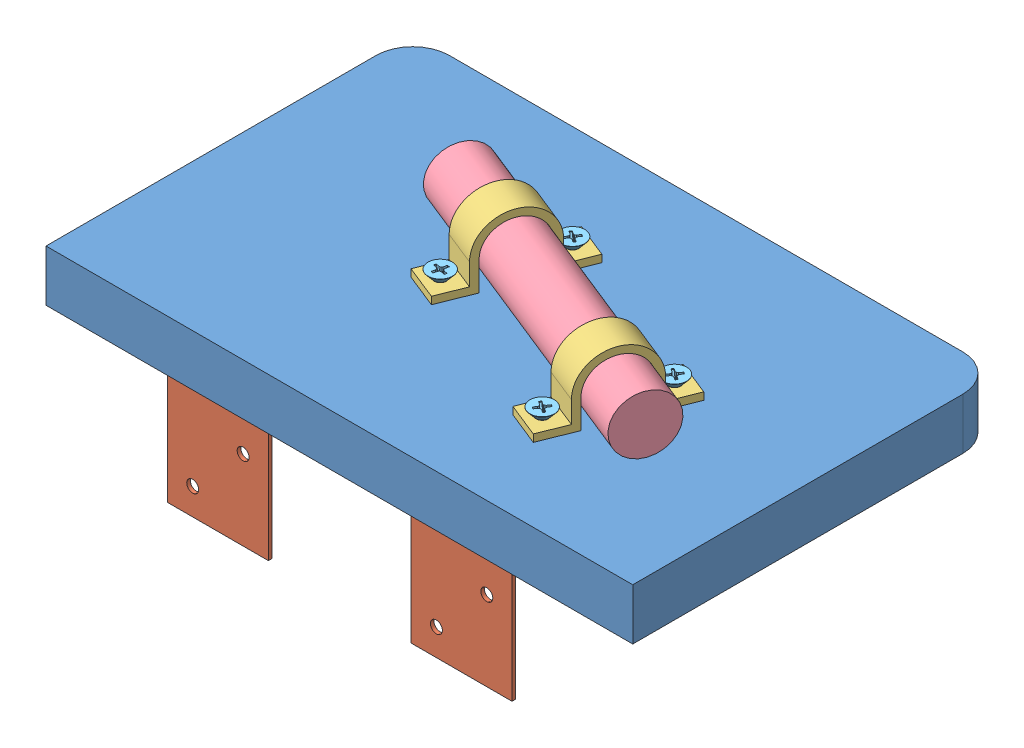
SolidWorks assembly Assemsight, configuration Default. Lengths in mm.
Overall size (203.2 82.02 127).
16 component instances, 7 part files, 18 mates.
Components (placement in the parent):
- RampSight-1: RampSight [Default] at (38.0656 138.4152 220.9267) size (203.2 17.78 127)
- screwangle-1: screwangle [Default] at (-4.0031 138.4152 259.014) x (0 0 -1) z (0 -1 0) size (50.8 34.92 38.1)
- screwangle-2: screwangle [Default] at (80.3757 138.4152 259.014) x (0 0 -1) z (0 -1 0) size (50.8 34.92 38.1)
- LaserStrap-3: LaserStrap [Default] at (76.1001 166.1978 233.9353) x (0.37234 0 -0.928096) z (0.928096 0 0.37234) size (45.4 22.54 12.7)
- LaserStrap-4: LaserStrap [Default] at (17.166 166.1978 210.2918) x (0.37234 0 -0.928096) z (0.928096 0 0.37234) size (45.4 22.54 12.7)
- laserpointereal-3: laserpointereal [Default] at (-2.9774 166.1952 201.3092) x (-0.371391 0.071332 0.925732) z (0.928096 0 0.37234) size (30.2 30.2 115)
- Part1^Assemsight-1: Part1^Assemsight [Default] at origin (virtual)
- Part2^Assemsight-1: Part2^Assemsight [Default] at origin (virtual)
- sightscrew-1: sightscrew [90031A194] at (16.8102 154.9836 228.2328) x (0 -1 0) z (-0.202266 0 0.979331) size (12.7 8.43 8.43)
- sightscrew-2: sightscrew [90031A194] at (-12.7344 140.9552 245.9965) x (0 1 0) z (-0.546944 0 0.837169) size (12.7 8.43 8.43)
- sightscrew-3: sightscrew [90031A194] at (88.8656 154.9836 219.1703) x (0 -1 0) z (-0.546944 0 0.837169) size (12.7 8.43 8.43)
- sightscrew-4: sightscrew [90031A194] at (4.4741 140.9552 270.7615) x (0 1 0) z (-0.546944 0 0.837169) size (12.7 8.43 8.43)
- sightscrew-5: sightscrew [90031A194] at (88.8529 140.9552 270.7615) x (0 1 0) z (-0.546944 0 0.837169) size (12.7 8.43 8.43)
- sightscrew-7: sightscrew [90031A194] at (75.7444 154.9836 251.8764) x (0 -1 0) z (-0.546944 0 0.837169) size (12.7 8.43 8.43)
- sightscrew-8: sightscrew [90031A194] at (71.6444 140.9552 245.9965) x (0 1 0) z (-0.546944 0 0.837169) size (12.7 8.43 8.43)
- sightscrew-9: sightscrew [90031A194] at (29.9315 154.9836 195.5267) x (0 -1 0) z (-0.546944 0 0.837169) size (12.7 8.43 8.43)
Mates (geometry in assembly coordinates):
- Coincident1: coincident: circle of RampSight-1; circle of screwangle-1
- Parallel1: parallel: plane of RampSight-1 through (-63.5344 156.1952 284.4267) normal (0 0 1); line of screwangle-1 through (13.4594 138.4152 284.414) axis (-1 0 0)
- Coincident6: coincident: circle of RampSight-1; circle of screwangle-2
- Parallel2: parallel: line of RampSight-1 through (-63.5344 138.4152 284.4267) axis (1 0 0); line of screwangle-2 through (97.8382 138.4152 284.414) axis (-1 0 0)
- Coincident20: coincident: circle of RampSight-1; circle of LaserStrap-3
- Coincident23: coincident: circle of RampSight-1; circle of LaserStrap-4
- Concentric18: concentric: cylinder of LaserStrap-3 through (88.1984 166.1952 237.8877) axis (-0.928096 0 -0.37234) radius 10; cylinder of laserpointereal-3 through (103.7537 166.1952 244.1283) axis (-0.928096 0 -0.37234) radius 10
- Concentric19: concentric: cylinder of LaserStrap-4 through (29.2643 166.1952 214.2441) axis (-0.928096 0 -0.37234) radius 10; cylinder of laserpointereal-3 through (103.7537 166.1952 244.1283) axis (-0.928096 0 -0.37234) radius 10
- Concentric20: concentric: circle of LaserStrap-4; circle of sightscrew-1
- Concentric21: concentric: circle of LaserStrap-4; circle of sightscrew-1
- Coincident24: coincident: circle of LaserStrap-4; cone of sightscrew-1 through (16.8102 158.7936 228.2328) axis (0 -1 0)
- Coincident25: coincident: circle of LaserStrap-3; cone of sightscrew-7 through (75.7444 158.7936 251.8764) axis (0 -1 0)
- Coincident27: coincident: circle of LaserStrap-4; cone of sightscrew-9 through (29.9315 158.7936 195.5267) axis (0 -1 0)
- Coincident28: coincident: circle of LaserStrap-3; cone of sightscrew-3 through (88.8656 158.7936 219.1703) axis (0 -1 0)
- Coincident29: coincident: circle of screwangle-2; cone of sightscrew-8 through (71.6444 137.1452 245.9965) axis (0 1 0)
- Coincident30: coincident: circle of screwangle-2; cone of sightscrew-5 through (88.8529 137.1452 270.7615) axis (0 1 0)
- Coincident31: coincident: circle of screwangle-1; cone of sightscrew-2 through (-12.7344 137.1452 245.9965) axis (0 1 0)
- Coincident32: coincident: circle of screwangle-1; cone of sightscrew-4 through (4.4741 137.1452 270.7615) axis (0 1 0)
